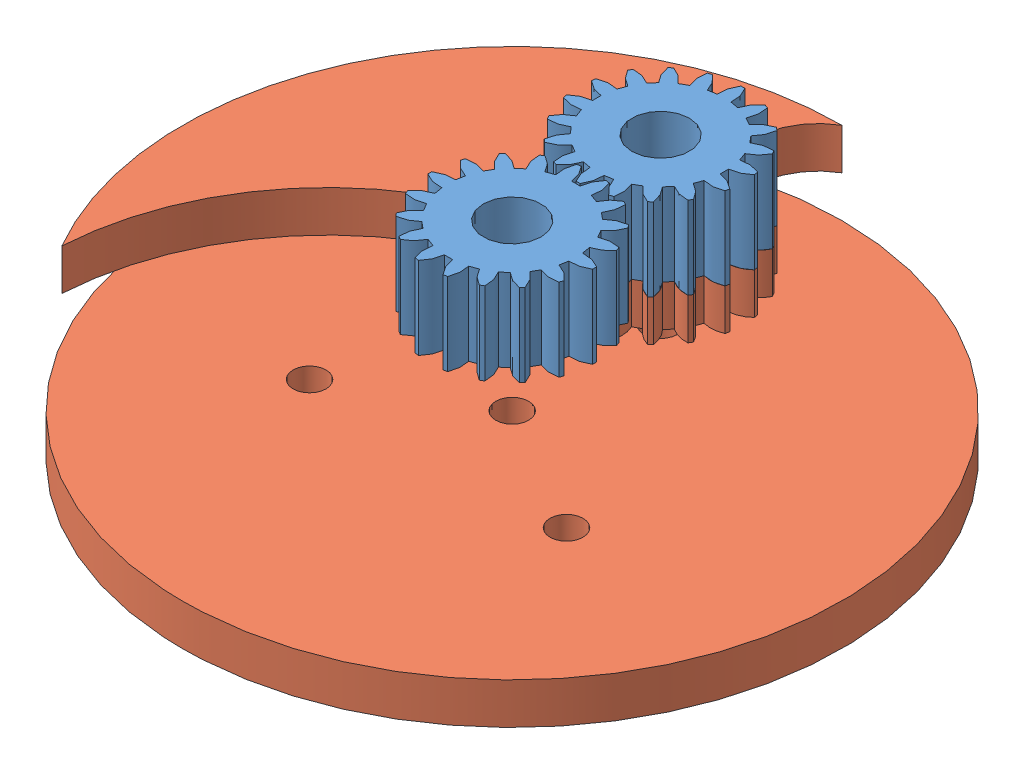
SolidWorks assembly Assem1, configuration Default. Lengths in mm.
Overall size (50 15 60).
3 component instances, 2 part files, 6 mates.
Components (placement in the parent):
- Gear 1M 18T D7-1: Gear 1M 18T D7 [GB - Spur gear 1M 18T 20PA 10FW ---S18A75H50L3.0N] at (-24.1363 -6.6501 26.6869) x (0 1 0) z (-1 0 0) size (10 19.78 20)
- Part3-1: Part3 [Default] at (-24.1363 -21.6501 26.6869) size (80 15 80)
- Gear 1M 18T D7-2: Gear 1M 18T D7 [GB - Spur gear 1M 18T 20PA 10FW ---S18A75H50L3.0N] at (-24.1363 -6.6501 8.6869) x (0 1 0) z (0 0 -1) size (10 19.78 20)
Mates (geometry in assembly coordinates):
- Concentric1: concentric anti-aligned: cylinder of Gear 1M 18T D7-1 through (-24.1363 43.35 26.6869) axis (0 -1 0) radius 3.5; circle of Part3-1
- Parallel1: parallel aligned: line of Gear 1M 18T D7-1 through (-24.1363 3.3499 26.6869) axis (0 0 -1); line of Part3-1 through (-24.1363 -16.6501 26.6869) axis (0 0 -1)
- Concentric2: concentric aligned: circle of Part3-1; circle of Gear 1M 18T D7-2
- Perpendicular1: perpendicular: line of Part3-1 through (-24.1363 -16.6501 26.6869) axis (0 0 -1); line of Gear 1M 18T D7-2 through (-24.1363 3.3499 8.6869) axis (1 0 0)
- Coincident3: coincident aligned: plane of Gear 1M 18T D7-1 through (-24.1363 3.3499 26.6869) normal (0 1 0); plane of Gear 1M 18T D7-2 through (-24.1363 3.3499 8.6869) normal (0 1 0)
- Distance1: distance = 10 mm anti-aligned: plane of Part3-1 through (-24.1363 -16.6501 26.6869) normal (0 1 0); plane of Gear 1M 18T D7-2 through (-24.1363 -6.6501 8.6869) normal (0 -1 0)
